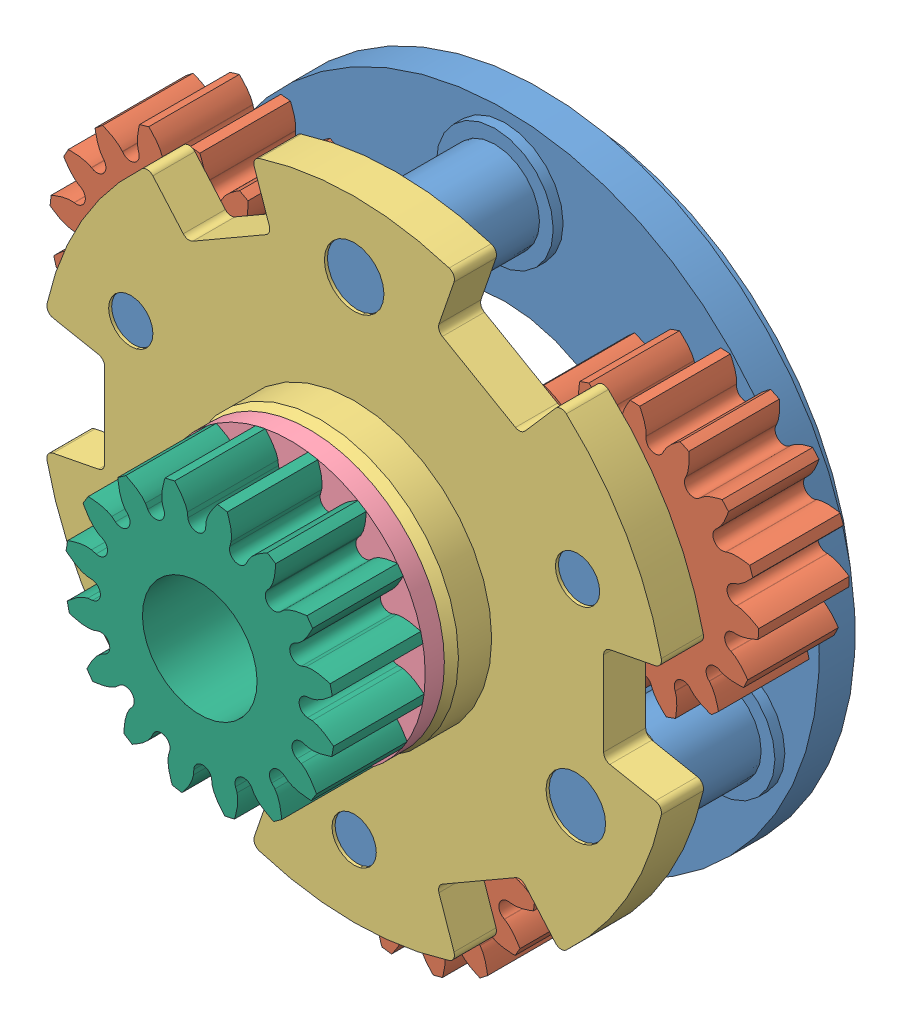
SolidWorks assembly TanSet, configuration Default. Lengths in mm.
Overall size (26.79 24.47 12.04).
9 component instances, 6 part files, 12 mates.
Components (placement in the parent):
- TanArmDisk-1: TanArmDisk [Default] at (5.948 13.3306 15.3794) size (20.9 20.9 6.81)
- TanPlanetGear-1: TanPlanetGear [Default] at (-1.4754 16.4817 16.9034) x (-0.626229 0.779639 0) z (0 0 1) size (8.71 8.71 3.01)
- TanPlanetGear-2: TanPlanetGear [Default] at (13.3714 16.4817 16.9034) x (-0.433897 -0.900963 0) z (0 0 1) size (8.71 8.71 3.01)
- TanPlanetGear-3: TanPlanetGear [Default] at (5.948 5.2661 16.9034) x (0.864945 -0.501867 0) z (0 0 1) size (8.71 8.71 3.01)
- TanDriveDisk-1: TanDriveDisk [Default] at (5.948 13.3306 21.577) x (-1 0 0) z (0 0 -1) size (20.43 20.9 2.98)
- TanSunGear-1: TanSunGear [Default] at (0.9435 9.3431 16.7271) x (0.985787 -0.167998 0) z (0 0 1) size (8.97 8.97 6.65)
  - TanIntermediaryPlate-1: TanIntermediaryPlate [Default] at (4.2635 4.7716 6.3357) size (8.97 8.97 0.64)
  - TanSpurSmall-1: TanSpurSmall [Default] at (4.2635 4.7716 3.3258) x (-1 0 0) z (0 0 1) size (5.78 5.84 3.01)
  - TanSpurLarge-1: TanSpurLarge [Default] at (4.2635 4.7716 6.9707) size (8.97 8.97 3.01)
Mates (geometry in assembly coordinates):
- Concentric1: concentric aligned: cylinder of TanArmDisk-1 through (-1.4754 16.4817 20.0784) axis (0 0 -1) radius 0.9779; cylinder of TanPlanetGear-1 through (-1.4754 16.4817 19.9133) axis (0 0 -1) radius 1.016
- Concentric2: concentric aligned: cylinder of TanArmDisk-1 through (5.948 5.2661 20.0784) axis (0 0 -1) radius 0.9779; cylinder of TanPlanetGear-3 through (5.948 5.2661 19.9133) axis (0 0 -1) radius 1.016
- Concentric3: concentric aligned: cylinder of TanArmDisk-1 through (13.3714 16.4817 20.0784) axis (0 0 -1) radius 0.9779; cylinder of TanPlanetGear-2 through (13.3714 16.4817 19.9133) axis (0 0 -1) radius 1.016
- Coincident1: coincident anti-aligned: plane of TanArmDisk-1 through (13.3714 16.4817 16.9034) normal (0 0 1); plane of TanPlanetGear-2 through (13.3714 16.4817 16.9034) normal (0 0 -1)
- Coincident2: coincident anti-aligned: plane of TanArmDisk-1 through (5.948 5.2661 16.9034) normal (0 0 1); plane of TanPlanetGear-3 through (5.948 5.2661 16.9034) normal (0 0 -1)
- Coincident3: coincident anti-aligned: plane of TanArmDisk-1 through (-1.4754 16.4817 16.9034) normal (0 0 1); plane of TanPlanetGear-1 through (-1.4754 16.4817 16.9034) normal (0 0 -1)
- Concentric4: concentric aligned: cylinder of TanArmDisk-1 through (5.948 21.4586 21.4754) axis (0 0 -1) radius 0.9906; cylinder of TanDriveDisk-1 through (5.948 21.4586 21.577) axis (0 0 -1) radius 0.9906
- Coincident4: coincident anti-aligned: plane of TanArmDisk-1 through (5.948 21.4586 20.0784) normal (0 0 1); plane of TanDriveDisk-1 through (5.948 21.4586 20.0784) normal (0 0 -1)
- Concentric6: concentric aligned: cylinder of TanArmDisk-1 through (-1.4754 16.4817 21.4754) axis (0 0 -1) radius 0.7366; cylinder of TanDriveDisk-1 through (-1.4754 16.4817 21.577) axis (0 0 -1) radius 0.7366
- Coincident5: coincident anti-aligned: plane of TanDriveDisk-1 through (5.948 13.3306 23.0629) normal (0 0 1); plane of TanSunGear-1/TanIntermediaryPlate-1 through (5.948 13.3306 23.0629) normal (0 0 -1)
- Concentric7: concentric anti-aligned: cylinder of TanDriveDisk-1 through (5.948 13.3306 20.0784) axis (0 0 1) radius 4.572; cylinder of TanSunGear-1/TanIntermediaryPlate-1 through (5.948 13.3306 23.6979) axis (0 0 -1) radius 4.4831
- GearMate1: gear = 5.842 : 5.9944 mm: circle of TanDriveDisk-1; circle of TanSunGear-1/TanSpurSmall-1
